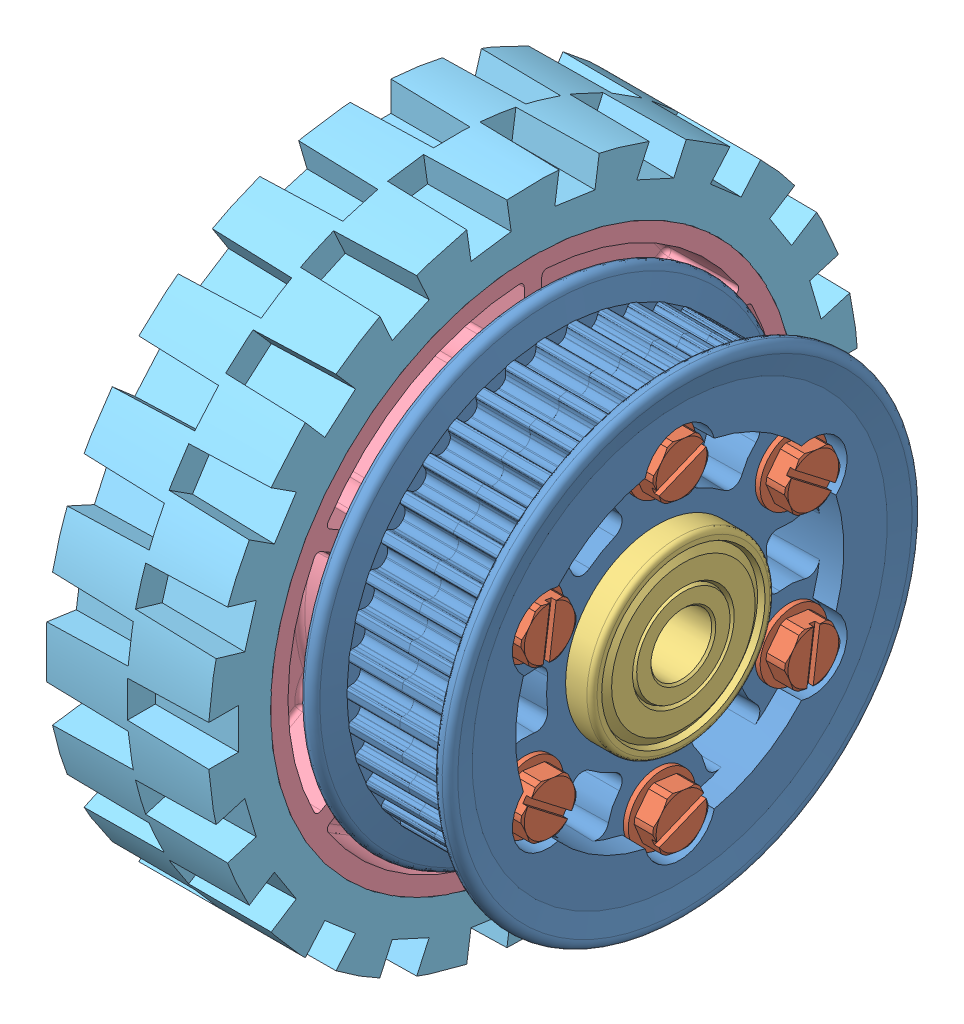
SolidWorks assembly 2014 KoP - 4 HiGrip and Single 42 HTD Pulley, configuration Default. Lengths in mm.
Overall size (56.51 101.6 101.6).
13 component instances, 5 part files, 12 mates.
Components (placement in the parent):
- 42 tooth HTD Pulley half 2014-3: 42 tooth HTD Pulley half 2014 [Default] at (20.6365 -5.3771 -25.0455) x (1 0 0) z (0 -0.866057 0.499945) size (13 74.23 74.23)
- 42 tooth HTD Pulley half 2014-4: 42 tooth HTD Pulley half 2014 [Default] at (37.2989 -5.3771 -25.0455) x (-1 0 0) z (0 -0.866015 0.500018) size (13 74.23 74.23)
- 10-24 Hex Washer Rolling x 1.25-2: 10-24 Hex Washer Rolling x 1.25 [93882A213] at (36.2829 -17.2838 -45.6675) x (0 0.991147 -0.132773) z (1 0 0) size (10.52 10.52 35.59)
- 10-24 Hex Washer Rolling x 1.25-8: 10-24 Hex Washer Rolling x 1.25 [93882A213] at (36.2829 6.5287 -45.668) x (0 0.610558 0.791972) z (1 0 0) size (10.52 10.52 35.59)
- 10-24 Hex Washer Rolling x 1.25-9: 10-24 Hex Washer Rolling x 1.25 [93882A213] at (36.2829 18.4354 -25.046) x (0 -0.380589 0.924744) z (1 0 0) size (10.52 10.52 35.59)
- 10-24 Hex Washer Rolling x 1.25-10: 10-24 Hex Washer Rolling x 1.25 [93882A213] at (36.2829 6.5296 -4.4236) x (0 -0.991147 0.132773) z (1 0 0) size (10.52 10.52 35.59)
- 10-24 Hex Washer Rolling x 1.25-11: 10-24 Hex Washer Rolling x 1.25 [93882A213] at (36.2829 -17.2829 -4.4231) x (0 -0.610558 -0.791972) z (1 0 0) size (10.52 10.52 35.59)
- 10-24 Hex Washer Rolling x 1.25-12: 10-24 Hex Washer Rolling x 1.25 [93882A213] at (36.2829 -29.1896 -25.045) x (0 0.380589 -0.924744) z (1 0 0) size (10.52 10.52 35.59)
- 1614Z Bearing-1: 1614Z Bearing [Default] at (-11.05 -5.3771 -25.0455) x (0 0.217345 -0.976095) z (1 0 0) size (28.57 28.57 9.53)
- 1614Z Bearing-2: 1614Z Bearing [Default] at (35.6479 -5.3771 -25.0455) x (0 0.48768 0.873023) z (-1 0 0) size (28.57 28.57 9.53)
- 4 in HiGrip Wheel-1: 4 in HiGrip Wheel [Default] at (12.2416 -7.9007 -27.5798) x (1 0 0) z (0 0.000021 1) size (34.92 101.6 101.6)
  - 4in 2013 Hub-1: 4in 2013 Hub [Default] at (-8.0517 2.5236 2.5343) size (34.92 82.55 82.55)
  - 4 in tread-1: 4 in tread [Default] at (-8.0517 2.5236 2.5343) size (25.4 101.6 101.6)
Mates (geometry in assembly coordinates):
- Concentric2: concentric anti-aligned: cylinder of 42 tooth HTD Pulley half 2014-3 through (27.05 -5.3771 -25.0455) axis (-1 0 0) radius 14.2875; cylinder of 42 tooth HTD Pulley half 2014-4 through (30.8854 -5.3771 -25.0455) axis (1 0 0) radius 14.2875
- Concentric6: concentric aligned: cylinder of 42 tooth HTD Pulley half 2014-3 through (27.5707 6.5279 -4.4226) axis (1 0 0) radius 4.1529; cylinder of 42 tooth HTD Pulley half 2014-4 through (27.6977 6.5279 -4.4226) axis (1 0 0) radius 4.1275
- Coincident2: coincident anti-aligned: plane of 42 tooth HTD Pulley half 2014-3 through (28.9677 10.613 2.9016) normal (1 0 0); plane of 42 tooth HTD Pulley half 2014-4 through (28.9677 -21.5838 -52.8676) normal (-1 0 0)
- Concentric11: concentric anti-aligned: cylinder of 42 tooth HTD Pulley half 2014-4 through (28.9677 -17.2838 -45.6675) axis (1 0 0) radius 2.54; cylinder of 10-24 Hex Washer Rolling x 1.25-2 through (37.0499 -17.2838 -45.6675) axis (-1 0 0) radius 5.2578
- Coincident6: coincident anti-aligned: plane of 42 tooth HTD Pulley half 2014-4 through (36.2829 -5.3771 -25.0455) normal (1 0 0); plane of 10-24 Hex Washer Rolling x 1.25-2 through (36.2829 -16.6753 -41.1254) normal (-1 0 0)
- Concentric12: concentric anti-aligned: cylinder of 42 tooth HTD Pulley half 2014-4 through (30.8854 -5.3771 -25.0455) axis (1 0 0) radius 14.2875; cylinder of 1614Z Bearing-2 through (35.6479 -5.3771 -25.0455) axis (-1 0 0) radius 14.2875
- Coincident7: coincident anti-aligned: plane of 42 tooth HTD Pulley half 2014-4 through (30.8854 -5.3771 -25.0455) normal (1 0 0); plane of 1614Z Bearing-2 through (30.8854 -5.3771 -25.0455) normal (-1 0 0)
- Concentric13: concentric aligned: cylinder of 1614Z Bearing-1 through (-11.05 -5.3771 -25.0455) axis (1 0 0) radius 14.2875; cylinder of 4 in HiGrip Wheel-1/4in 2013 Hub-1 through (14.6675 -5.3771 -25.0455) axis (1 0 0) radius 14.2875
- Coincident9: coincident anti-aligned: circle of 1614Z Bearing-1; plane of 4 in HiGrip Wheel-1/4in 2013 Hub-1 through (-6.2875 -5.3771 -25.0455) normal (-1 0 0)
- Concentric14: concentric anti-aligned: cylinder of 10-24 Hex Washer Rolling x 1.25-8 through (36.2829 6.5287 -45.668) axis (-1 0 0) radius 1.8402; cylinder of 4 in HiGrip Wheel-1/4in 2013 Hub-1 through (-13.2725 6.5287 -45.668) axis (1 0 0) radius 1.9939
- Concentric15: concentric anti-aligned: cylinder of 1614Z Bearing-1 through (-11.05 -5.3771 -25.0455) axis (1 0 0) radius 4.7625; cylinder of 1614Z Bearing-2 through (35.6479 -5.3771 -25.0455) axis (-1 0 0) radius 4.7625
- Coincident10: coincident anti-aligned: plane of 42 tooth HTD Pulley half 2014-3 through (21.6525 -5.3771 -25.0455) normal (-1 0 0); plane of 4 in HiGrip Wheel-1/4in 2013 Hub-1 through (21.6525 -5.3771 -25.0455) normal (1 0 0)
